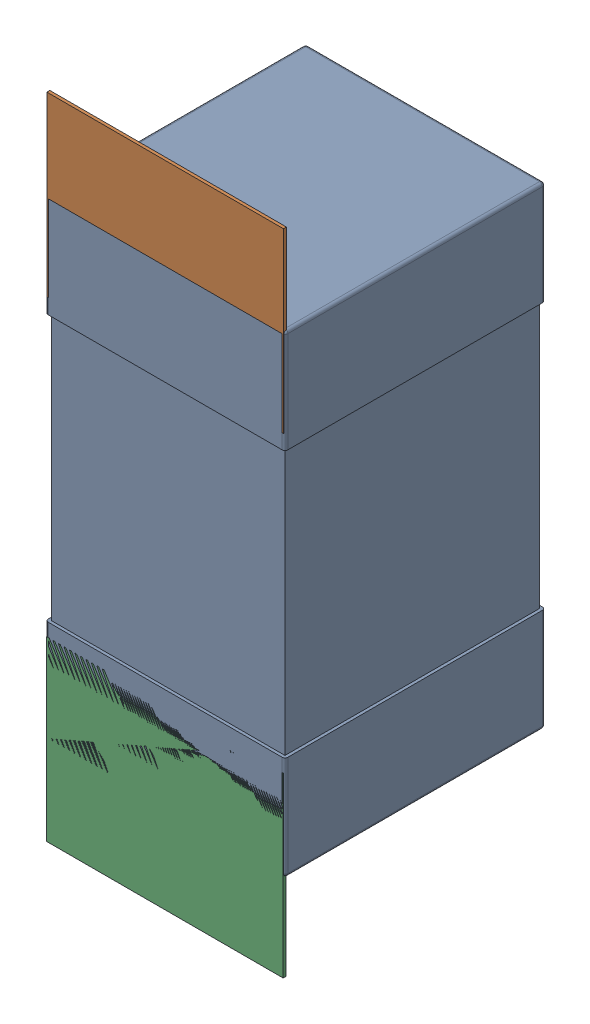
SolidWorks assembly C44, configuration Défaut. Lengths in mm.
Overall size (0.81 2.19 0.88).
5 component instances, 2 part files, 0 mates.
Components (placement in the parent):
- 0603_C-1: 0603_C [Défaut] at (15.8455 -9.4036 -2.0818) x (0 1 0) z (0 0 -1) size (1.6 0.81 0.88)
- 8260087904-1: 8260087904 [Défaut] at (15.8455 -8.1536 -2.0918) size (0.8 0.6 0.01)
  - Extruded_1211-1: Extruded_1211 [Défaut] at origin size (0.8 0.6 0.01)
- 8260087904-2: 8260087904 [Défaut] at (15.8443 -9.7485 -2.0918) size (0.8 0.6 0.01)
  - Extruded_1211-1: Extruded_1211 [Défaut] at origin size (0.8 0.6 0.01)
